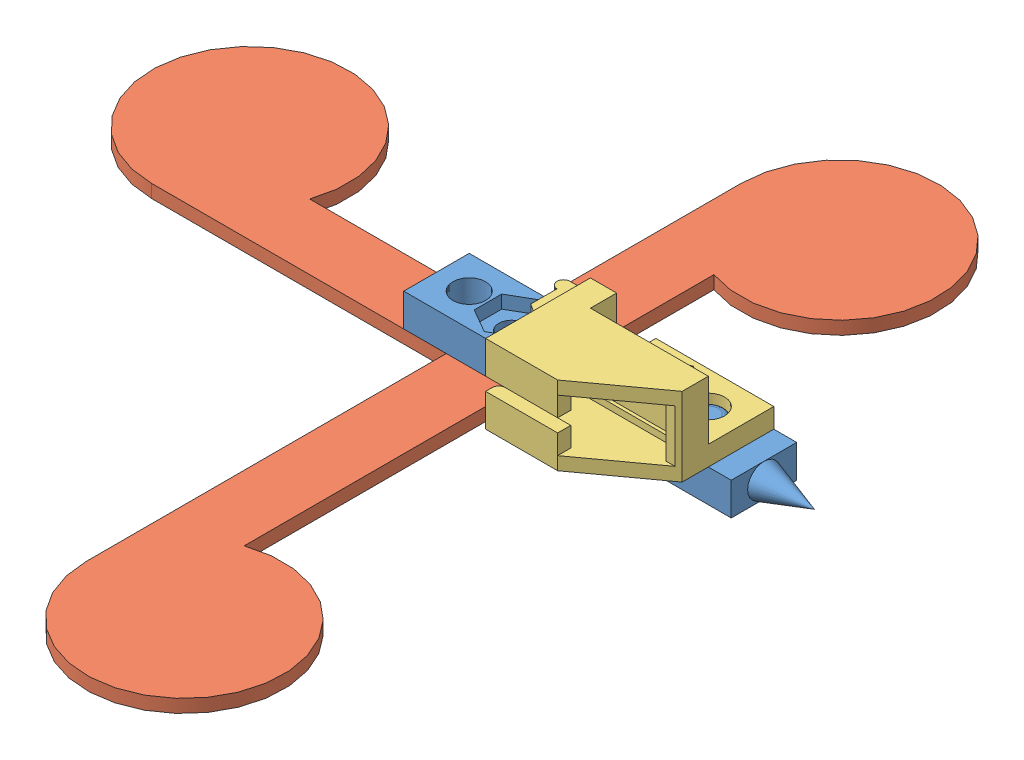
SolidWorks assembly MicronAscensionTracking-Concept, configuration Default. Lengths in mm.
Overall size (111.19 19 130).
3 component instances, 3 part files, 6 mates.
Components (placement in the parent):
- Pointer-TwoConnectors-1: Pointer-TwoConnectors [Default] at (-1.761 26.9887 48.5484) size (57.69 7 10)
- MicronPlate01-1: MicronPlate01 [Default] at (19.739 26.9887 3.5484) x (0 0 1) z (1 0 0) size (130 4 90)
- SensorHolderConnector_1.0-1: SensorHolderConnector_1.0 [Default] at (44.739 40.0202 50.8161) x (0 0 1) z (0 -1 0) size (22 26.1 12)
Mates (geometry in assembly coordinates):
- Coincident3: coincident anti-aligned: plane of Pointer-TwoConnectors-1 through (-1.761 31.9887 48.5484) normal (0 1 0); plane of SensorHolderConnector_1.0-1 through (42.739 31.9887 44.5484) normal (0 -1 0)
- Concentric3: concentric anti-aligned: cylinder of Pointer-TwoConnectors-1 through (33.239 26.9887 43.5484) axis (0 1 0) radius 2; circle of SensorHolderConnector_1.0-1
- Coincident6: coincident anti-aligned: plane of Pointer-TwoConnectors-1 through (-1.761 26.9887 48.5484) normal (0 -1 0); plane of MicronPlate01-1 through (-40.261 26.9887 33.5484) normal (0 1 0)
- Concentric5: concentric anti-aligned: circle of Pointer-TwoConnectors-1; circle of MicronPlate01-1
- Concentric6: concentric aligned: circle of Pointer-TwoConnectors-1; circle of MicronPlate01-1
- Concentric7: concentric aligned: circle of Pointer-TwoConnectors-1; circle of SensorHolderConnector_1.0-1
